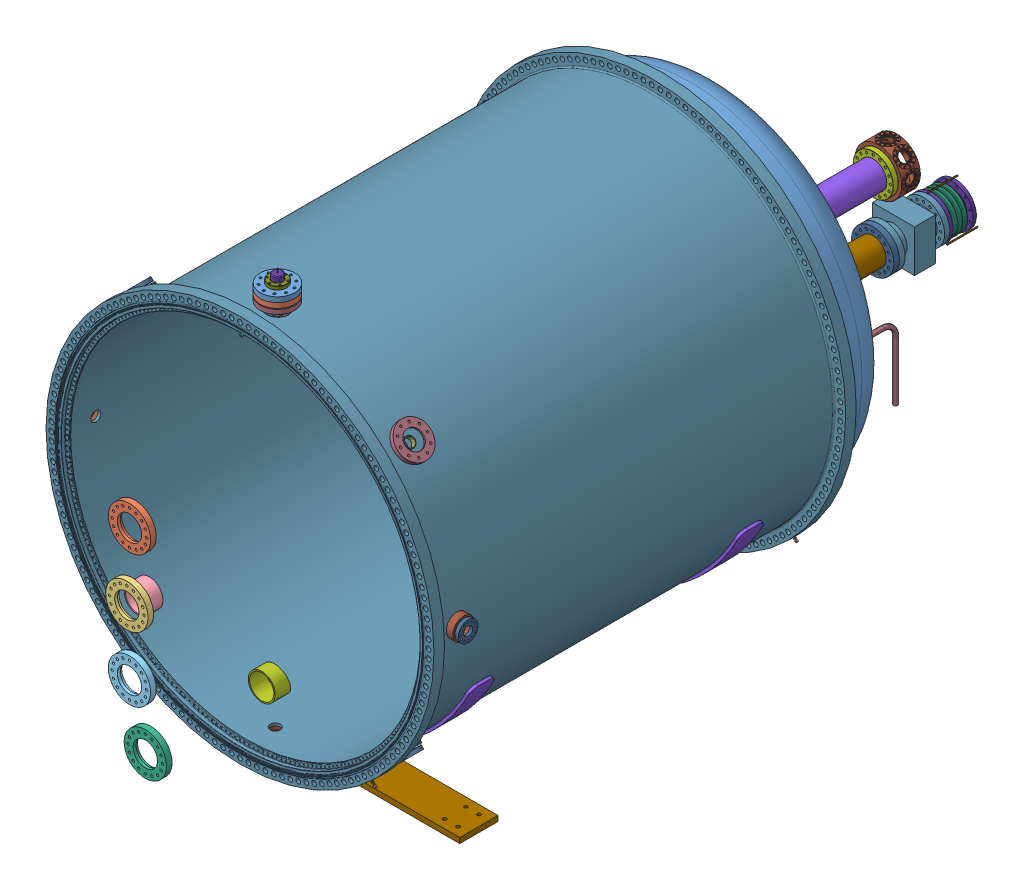
SolidWorks assembly 0201-ASSEMBLAGE, configuration Predeterminado. Lengths in mm.
Overall size (1480 1658.11 3261.35).
238 component instances, 64 part files, 0 mates.
Components (placement in the parent):
- pressure_vessel1_jordi-1: pressure_vessel1_jordi [Predeterminado] at (41.4592 923 146.4) x (-1 0 0) z (0 0 1) size (1480 1658.11 3261.35)
  - mount_hardware-1: mount_hardware [Predeterminado] at (0 -3 0) size (1220 87.2 1155)
    - corner-free-1: corner-free [Predeterminado] at (-0.75 0 12.9) size (150 87 135)
      - key_free.1-1: key_free.1 [Predeterminado] at (0 0 -80) size (20 23.2 20)
      - key_free.1-2: key_free.1 [Predeterminado] at origin size (20 23.2 20)
      - fastener_set.1.1-1: fastener_set.1.1 [Predeterminado] at (0 0 -1040.4) size (50 87 50)
        - washer-1: washer [Predeterminado] at origin size (50 5 50)
        - m16-2_hhexnut-1: m16-2_hhexnut [Predeterminado] at (543.2477 766.8 336.1) size (24 16 27.71)
        - m16-stud-1: m16-stud [Predeterminado] at origin size (16 87 16)
      - fastener_set.1.1-2: fastener_set.1.1 [Predeterminado] at (0 0 -960.4) size (50 87 50)
        - washer-1: washer [Predeterminado] at origin size (50 5 50)
        - m16-2_hhexnut-1: m16-2_hhexnut [Predeterminado] at (543.2477 766.8 336.1) size (24 16 27.71)
        - m16-stud-1: m16-stud [Predeterminado] at origin size (16 87 16)
      - pad-free-1: pad-free [Predeterminado] at (1.4954 0 -288.2) x (-1 0 0) z (0 0 -1) size (150 6 135)
    - corner_hardware_long_slide-1: corner_hardware_long_slide [Predeterminado] at (0.7454 0 -275.3) x (-1 0 0) z (0 0 -1) size (150 87 135)
      - fastener_set.1.1-1: fastener_set.1.1 [Predeterminado] at (1086.4954 0 752.2) x (-1 0 0) z (0 0 -1) size (50 87 50)
        - washer-1: washer [Predeterminado] at origin size (50 5 50)
        - m16-2_hhexnut-1: m16-2_hhexnut [Predeterminado] at (543.2477 766.8 336.1) size (24 16 27.71)
        - m16-stud-1: m16-stud [Predeterminado] at origin size (16 87 16)
      - fastener_set.1.1-2: fastener_set.1.1 [Predeterminado] at (1086.4954 0 672.2) x (-1 0 0) z (0 0 -1) size (50 87 50)
        - washer-1: washer [Predeterminado] at origin size (50 5 50)
        - m16-2_hhexnut-1: m16-2_hhexnut [Predeterminado] at (543.2477 766.8 336.1) size (24 16 27.71)
        - m16-stud-1: m16-stud [Predeterminado] at origin size (16 87 16)
      - bearing_pad_1-1: bearing_pad_1 [Predeterminado] at origin size (150 6 135)
      - key.1-1: key.1 [Predeterminado] at origin size (26 23.2 30)
      - key.1-2: key.1 [Predeterminado] at (0 0 -80) size (26 23.2 30)
    - corner_hardware_transverse_slide-1: corner_hardware_transverse_slide [Predeterminado] at (-1 0 -8) size (149.75 87 135)
      - fastener_set.1.1-1: fastener_set.1.1 [Predeterminado] at (0 0 80) size (50 87 50)
        - washer-1: washer [Predeterminado] at origin size (50 5 50)
        - m16-2_hhexnut-1: m16-2_hhexnut [Predeterminado] at (543.2477 766.8 336.1) size (24 16 27.71)
        - m16-stud-1: m16-stud [Predeterminado] at origin size (16 87 16)
      - fastener_set.1.1-2: fastener_set.1.1 [Predeterminado] at origin size (50 87 50)
        - washer-1: washer [Predeterminado] at origin size (50 5 50)
        - m16-2_hhexnut-1: m16-2_hhexnut [Predeterminado] at (543.2477 766.8 336.1) size (24 16 27.71)
        - m16-stud-1: m16-stud [Predeterminado] at origin size (16 87 16)
      - bearing_pad-1: bearing_pad [Predeterminado] at origin size (149.75 6 135)
      - key-1: key [Predeterminado] at (127.1477 0 959.3477) x (0 0 -1) z (1 0 0) size (26 23.2 30)
      - key-2: key [Predeterminado] at (127.1477 0 879.3477) x (0 0 -1) z (1 0 0) size (26 23.2 30)
    - corner_fixed-1: corner_fixed [Predeterminado] at origin size (150 87 135)
      - fastener_set.1.1-1: fastener_set.1.1 [Predeterminado] at (-1085.75 0.2 72.5) size (50 87 50)
        - washer-1: washer [Predeterminado] at origin size (50 5 50)
        - m16-2_hhexnut-1: m16-2_hhexnut [Predeterminado] at (543.2477 766.8 336.1) size (24 16 27.71)
        - m16-stud-1: m16-stud [Predeterminado] at origin size (16 87 16)
      - fastener_set.1.1-2: fastener_set.1.1 [Predeterminado] at (-1085.75 0.2 -7.5) size (50 87 50)
        - washer-1: washer [Predeterminado] at origin size (50 5 50)
        - m16-2_hhexnut-1: m16-2_hhexnut [Predeterminado] at (543.2477 766.8 336.1) size (24 16 27.71)
        - m16-stud-1: m16-stud [Predeterminado] at origin size (16 87 16)
      - pad-fixed-1: pad-fixed [Predeterminado] at (-0.75 0 -7.5) size (150 6 135)
  - tracking_head_assem_jordi-1: tracking_head_assem_jordi [Predeterminado] at (0 0 -17.4) x (-1 0 0) z (0 0 -1) size (1480 1510.05 550.83)
    - Hexagon_Socket_Head_Cap_Screw_5_16-18x1_255_ANSI_B18.3-1: Hexagon_Socket_Head_Cap_Screw_5_16-18x1_255_ANSI_B18.3 [Predeterminado] at (0 -660 -681.9) x (1 0 0) z (0 0 -1) size (11.91 11.91 39.8)
    - Hexagon_Socket_Head_Cap_Screw_5_16-18x1_255_ANSI_B18.3-2: Hexagon_Socket_Head_Cap_Screw_5_16-18x1_255_ANSI_B18.3 [Predeterminado] at (0 660 -681.5) x (-1 0 0) z (0 0 -1) size (11.91 11.91 39.8)
    - O-ring_press.1.1-1: O-ring_press.1.1 [Predeterminado] at (0 0 61.9) x (-1 0 0) z (0 0 -1) size (1377.4 1377.4 3.81)
    - O-ring_H2o-1: O-ring_H2o [Predeterminado] at (0 0 61.5) x (-1 0 0) z (0 0 -1) size (1392 1392 2.61)
    - head_weldment.1-1: head_weldment.1 [Predeterminado] at (0 0 -17.4) x (-1 0 0) z (0 0 -1) size (1480 1510.05 550.83)
      - reinforcement.axial.1.1.1-1: reinforcement.axial.1.1.1 [Predeterminado] at (0 -13.7355 -284.0742) x (1 0 0) z (0 0.183956 -0.982934) size (203.29 202.99 30.7)
      - nozzle_aux_l.2-1: nozzle_aux_l.2 [Predeterminado] at (0 0 -282.8) x (1 0 0) z (0 0 -1) size (165 165 21.44)
        - flange_aux_2-1: flange_aux_2 [Predeterminado] at (0 0 -69.4114) x (-1 0 0) z (0 0 -1) size (165 165 21.44)
      - nozzle_axial-1: nozzle_axial [Predeterminado] at (0 0 -282.8) x (-1 0 0) z (0 0 -1) size (165 165 85.73)
        - flange_1-1: flange_1 [Predeterminado] at (0 250 -79.4114) x (1 0 0) z (0 0 -1) size (165 165 21.44)
        - tube-1: tube [Predeterminado] at (0 0 -242.4894) size (101.6 101.6 74.63)
      - nozzle_aux_l-1: nozzle_aux_l [Predeterminado] at (0 0 -282.8) x (-1 0 0) z (0 0 -1) size (440 939.85 440)
        - nozzle_auxiliary.1-1: nozzle_auxiliary.1 [Predeterminado] at (0 -250 -242.8779) x (-1 0 0) z (0 0 1) size (440 440 440)
        - nozzle_auxiliary.1-2: nozzle_auxiliary.1 [Predeterminado] at (0 250 -242.8779) size (440 440 440)
        - flange_aux_1-1: flange_aux_1 [Predeterminado] at (0 0 -69.4114) x (-1 0 0) z (0 0 -1) size (165 165 21.44)
      - head_O_ring-1: head_O_ring [Predeterminado] at (0 0 -17.4) x (-1 0 0) z (0 0 -1) size (1480 1480 359.44)
      - nozzle_hv-1: nozzle_hv [Predeterminado] at (0 272.0886 -282.8) x (-1 0 0) z (0 0 -1) size (496.82 496.82 496.82)
        - flange_aux-1: flange_aux [Predeterminado] at (0 0 -9.4114) x (-1 0 0) z (0 0 -1) size (165 165 21.44)
        - nozzle_auxiliary-1: nozzle_auxiliary [Predeterminado] at (0 250 217.1221) size (496.82 496.82 496.82)
      - reinforcement.axial-1: reinforcement.axial [Predeterminado] at (0 0 -282.8) x (-1 0 0) z (0 0 -1) size (203.28 203.96 19.57)
      - reinforcement.axial.1.1.1-2: reinforcement.axial.1.1.1 [Predeterminado] at (0 13.7355 -284.0742) x (-1 0 0) z (0 -0.183956 -0.982934) size (203.29 202.99 30.7)
      - reinforcement.axial.1.2-1: reinforcement.axial.1.2 [Predeterminado] at (0 28.6873 -288.5308) x (-1 0 0) z (0 -0.384203 -0.923249) size (193.14 205.75 36.46)
  - main_cyl_vessel-1: main_cyl_vessel [Predeterminado] at origin size (1480 1618.11 1626.05)
    - barrel_weldment.1-1: barrel_weldment.1 [Predeterminado] at origin size (1480 1537 1600)
      - support.1.1-1: support.1.1 [Predeterminado] at (0 0 882.5) size (1271.75 508.59 147.26)
        - pad-1: pad [Predeterminado] at (0 0 47.5) x (0.999999 0.001635 0) z (0 0 1) size (1271.08 410.55 147.26)
        - base_1-1: base_1 [Predeterminado] at (-0.75 27 0) size (1250 20 145)
        - plate.1-1: plate.1 [Predeterminado] at origin size (1230 442.67 145)
      - support.1-1: support.1 [Predeterminado] at (0 0 -137.5) size (1271.75 508.59 147.26)
        - base.1-1: base.1 [Predeterminado] at (0.7454 27 -1027.8) x (-1 0 0) z (0 0 -1) size (1250 20 145)
        - plate.1-1: plate.1 [Predeterminado] at origin size (1230 442.67 145)
        - pad-1: pad [Predeterminado] at (0 0 47.5) x (0.999999 0.001635 0) z (0 0 1) size (1271.08 410.55 147.26)
      - half_nipple_DN40_mdc_401002.3-1: half_nipple_DN40_mdc_401002.3 [Predeterminado] at (-504.8778 504.8778 525) x (-0.105943 -0.105943 -0.988712) z (-0.707107 0.707107 0) size (85.39 85.39 50.95)
        - flange_flat-1: flange_flat [Predeterminado] at (0 0 10.6864) x (0.988712 -0.149826 0) z (0 0 1) size (75 75 15)
        - tube_3-1: tube_3 [Predeterminado] at origin size (36 36 44.64)
      - half_nipple_DN40_mdc_401002.3-2: half_nipple_DN40_mdc_401002.3 [Predeterminado] at (-714.005 0 525) x (0 -0.149826 -0.988712) z (-1 0 0) size (85.39 85.39 50.95)
        - flange_flat-1: flange_flat [Predeterminado] at (0 0 10.6864) x (0.988712 -0.149826 0) z (0 0 1) size (75 75 15)
        - tube_3-1: tube_3 [Predeterminado] at origin size (36 36 44.64)
      - half_nipple_DN40_mdc_401002.3-3: half_nipple_DN40_mdc_401002.3 [Predeterminado] at (504.8778 -504.8778 525) x (0.105943 0.105943 -0.988712) z (0.707107 -0.707107 0) size (85.39 85.39 50.95)
        - flange_flat-1: flange_flat [Predeterminado] at (0 0 10.6864) x (0.988712 -0.149826 0) z (0 0 1) size (75 75 15)
        - tube_3-1: tube_3 [Predeterminado] at origin size (36 36 44.64)
      - half_nipple_DN40_mdc_401002.3-4: half_nipple_DN40_mdc_401002.3 [Predeterminado] at (714.005 0 525) x (0 0.149826 -0.988712) z (1 0 0) size (85.39 85.39 50.95)
        - flange_flat-1: flange_flat [Predeterminado] at (0 0 10.6864) x (0.988712 -0.149826 0) z (0 0 1) size (75 75 15)
        - tube_3-1: tube_3 [Predeterminado] at origin size (36 36 44.64)
      - half_nipple_DN40_mdc_401002.3-5: half_nipple_DN40_mdc_401002.3 [Predeterminado] at (504.8778 504.8778 525) x (-0.105943 0.105943 -0.988712) z (0.707107 0.707107 0) size (85.39 85.39 50.95)
        - flange_flat-1: flange_flat [Predeterminado] at (0 0 10.6864) x (0.988712 -0.149826 0) z (0 0 1) size (75 75 15)
        - tube_3-1: tube_3 [Predeterminado] at origin size (36 36 44.64)
      - half_nipple_DN40_mdc_401002.3-6: half_nipple_DN40_mdc_401002.3 [Predeterminado] at (0 714.005 525) x (-0.149826 0 -0.988712) z (0 1 0) size (85.39 85.39 50.95)
        - flange_flat-1: flange_flat [Predeterminado] at (0 0 10.6864) x (0.988712 -0.149826 0) z (0 0 1) size (75 75 15)
        - tube_3-1: tube_3 [Predeterminado] at origin size (36 36 44.64)
      - nozzle_DN75.1-1: nozzle_DN75.1 [Predeterminado] at (0 0 0.0857) x (0.707107 -0.707107 0) z (0 0 1) size (178.78 51.96 178.78)
        - tube_2-1: tube_2 [Predeterminado] at (0 -709.9952 516.5143) x (0.400618 0 -0.916245) z (0 -1 0) size (72 72 45.64)
        - flange_flat_DN75-1: flange_flat_DN75 [Predeterminado] at (0 -725.6914 516.5143) x (0.522753 0 -0.852484) z (0 -1 0) size (130 130 16.7)
      - nozzle_DN75.1-2: nozzle_DN75.1 [Predeterminado] at (0 0 0.0857) size (178.78 51.96 178.78)
        - tube_2-1: tube_2 [Predeterminado] at (0 -709.9952 516.5143) x (0.400618 0 -0.916245) z (0 -1 0) size (72 72 45.64)
        - flange_flat_DN75-1: flange_flat_DN75 [Predeterminado] at (0 -725.6914 516.5143) x (0.522753 0 -0.852484) z (0 -1 0) size (130 130 16.7)
      - main_vessel_bolt_flange_Oring-1: main_vessel_bolt_flange_Oring [Predeterminado] at (0 0 -140) size (1480 1480 1600)
    - half_nipple_DN40_mdc_401002.top-1: half_nipple_DN40_mdc_401002.top [Predeterminado] at (0 -729.005 516.6) x (0.400618 0 -0.916245) z (0 -1 0) size (261.68 261.68 242.65)
      - ft_CF75-1: ft_CF75 [Predeterminado] at (473.2537 -206.9251 -714.005) x (0.400618 0.916245 0) z (-0.916245 0.400618 0) size (198.72 242.65 198.72)
        - hv_feedthrough_assem-1: hv_feedthrough_assem [Predeterminado] at (45.0172 -129.75 1.9655) x (0.996195 0 0.087156) z (-0.087156 0 0.996195) size (183.43 242.65 183.43)
          - plunger-1: plunger [Predeterminado] at (0 73.6 0) size (7 109 7)
          - FT-vacom_50kV-1: FT-vacom_50kV [Predeterminado] at (-45.0172 110.4 1.9655) x (0.996195 0 -0.087156) z (0.087156 0 0.996195) size (94.08 221.5 94.08)
            - flange.1-1: flange.1 [Predeterminado] at (0 -744.3722 516.5143) x (-0.47895 0 0.877842) z (0 1 0) size (69.34 69.34 12.7)
            - insulator-1: insulator [Predeterminado] at (45.0172 -129.75 1.9655) x (0.996195 0 0.087156) z (-0.087156 0 0.996195) size (38.35 52 38.35)
            - conductor-1: conductor [Predeterminado] at (45.0172 -129.75 1.9655) x (0.996195 0 0.087156) z (-0.087156 0 0.996195) size (2 221.5 2)
          - DN75-40reducer3-1: DN75-40reducer3 [Predeterminado] at (0 -609.6136 516.5143) x (-0.222469 0 0.97494) z (0 1 0) size (130 130 19.05)
          - DN75_O-ring_adapter-1: DN75_O-ring_adapter [Predeterminado] at (0 -609.6136 516.5143) x (-0.753266 0 0.657716) z (0 -1 0) size (130 130 19.05)
    - pipe_tube5182K834-1: pipe_tube5182K834 [Predeterminado] at (-120.5041 -650.4585 -921.4) x (0.982918 -0.182173 0.026177) z (-0.182236 -0.983255 0) size (24.52 10 20.4)
      - p2_1-1: p2_1 [Predeterminado] at (-599.5111 15.6988 -1073.7738) x (-0.565333 0.04099 0.823844) z (-0.823844 0.021573 -0.566406) size (8.63 9.17 19.4)
      - p1_1-1: p1_1 [Predeterminado] at (-599.5111 15.6988 -1073.7738) x (-0.565333 0.04099 0.823844) z (-0.823844 0.021573 -0.566406) size (7.94 9.17 7.95)
    - pipe_tube5182K834-2: pipe_tube5182K834 [Predeterminado] at (-125.0832 -646.8042 679.3369) x (0.982918 -0.182173 0.026177) z (-0.182236 -0.983255 0) size (24.52 10 20.4)
      - p2_1-1: p2_1 [Predeterminado] at (-599.5111 15.6988 -1073.7738) x (-0.565333 0.04099 0.823844) z (-0.823844 0.021573 -0.566406) size (8.63 9.17 19.4)
      - p1_1-1: p1_1 [Predeterminado] at (-599.5111 15.6988 -1073.7738) x (-0.565333 0.04099 0.823844) z (-0.823844 0.021573 -0.566406) size (7.94 9.17 7.95)
    - SHOULDERBOLT_8XM6X10LG-1: SHOULDERBOLT_8XM6X10LG [Predeterminado] at (0 -670 649.6) x (0.949444 -0.313936 0) z (-0.313936 -0.949444 0) size (10 21.5 10)
  - flange_bolts_16mm-1: flange_bolts_16mm [Predeterminado] at origin size (71.93 1467.41 1731.8)
    - fastener_set_16mm.2-1: fastener_set_16mm.2 [Predeterminado] at (-6.2049 -94.8144 -477.8) x (-0.998993 0.044865 0) z (0 0 -1) size (37.08 37.41 131)
      - washer_17id_28od_4t.1-1: washer_17id_28od_4t.1 [Predeterminado] at (0 -620 422.1) size (28 28 3)
      - washer_17id_28od_4t.1-2: washer_17id_28od_4t.1 [Predeterminado] at (0 -620 505.1) x (-1 0 0) z (0 0 -1) size (28 28 3)
      - stud_M16x1F.1-1: stud_M16x1F.1 [Predeterminado] at (-94.3992 -1323.6965 -306) x (-0.991122 0.132957 0) z (0 0 1) size (16 16 131)
      - nut_M16x1F.1-1: nut_M16x1F.1 [Predeterminado] at (-232.2561 -1194.854 -156.9) x (-0.927184 0.374607 0) z (0 0 1) size (25.63 27.47 13)
      - nut_M16x1F.1-2: nut_M16x1F.1 [Predeterminado] at (-379.8395 -1110.0224 1084.1) x (0.790359 -0.612644 0) z (0 0 -1) size (25.63 27.47 13)
    - fastener_set_16mm.2-2: fastener_set_16mm.2 [Predeterminado] at (0 95 -477.8) x (1 0 0) z (0 0 -1) size (37.08 37.41 131)
      - washer_17id_28od_4t.1-1: washer_17id_28od_4t.1 [Predeterminado] at (0 -620 422.1) size (28 28 3)
      - washer_17id_28od_4t.1-2: washer_17id_28od_4t.1 [Predeterminado] at (0 -620 505.1) x (-1 0 0) z (0 0 -1) size (28 28 3)
      - stud_M16x1F.1-1: stud_M16x1F.1 [Predeterminado] at (-94.3992 -1323.6965 -306) x (-0.991122 0.132957 0) z (0 0 1) size (16 16 131)
      - nut_M16x1F.1-1: nut_M16x1F.1 [Predeterminado] at (-232.2561 -1194.854 -156.9) x (-0.927184 0.374607 0) z (0 0 1) size (25.63 27.47 13)
      - nut_M16x1F.1-2: nut_M16x1F.1 [Predeterminado] at (-379.8395 -1110.0224 1084.1) x (0.790359 -0.612644 0) z (0 0 -1) size (25.63 27.47 13)
    - fastener_set_16mm.2-3: fastener_set_16mm.2 [Predeterminado] at (0 -95 -477.8) x (-1 0 0) z (0 0 -1) size (37.08 37.41 131)
      - washer_17id_28od_4t.1-1: washer_17id_28od_4t.1 [Predeterminado] at (0 -620 422.1) size (28 28 3)
      - washer_17id_28od_4t.1-2: washer_17id_28od_4t.1 [Predeterminado] at (0 -620 505.1) x (-1 0 0) z (0 0 -1) size (28 28 3)
      - stud_M16x1F.1-1: stud_M16x1F.1 [Predeterminado] at (-94.3992 -1323.6965 -306) x (-0.991122 0.132957 0) z (0 0 1) size (16 16 131)
      - nut_M16x1F.1-1: nut_M16x1F.1 [Predeterminado] at (-232.2561 -1194.854 -156.9) x (-0.927184 0.374607 0) z (0 0 1) size (25.63 27.47 13)
      - nut_M16x1F.1-2: nut_M16x1F.1 [Predeterminado] at (-379.8395 -1110.0224 1084.1) x (0.790359 -0.612644 0) z (0 0 -1) size (25.63 27.47 13)
    - fastener_set_16mm.2-4: fastener_set_16mm.2 [Predeterminado] at (0 95 195) x (-1 0 0) z (0 0 1) size (37.08 37.41 131)
      - washer_17id_28od_4t.1-1: washer_17id_28od_4t.1 [Predeterminado] at (0 -620 422.1) size (28 28 3)
      - washer_17id_28od_4t.1-2: washer_17id_28od_4t.1 [Predeterminado] at (0 -620 505.1) x (-1 0 0) z (0 0 -1) size (28 28 3)
      - stud_M16x1F.1-1: stud_M16x1F.1 [Predeterminado] at (-94.3992 -1323.6965 -306) x (-0.991122 0.132957 0) z (0 0 1) size (16 16 131)
      - nut_M16x1F.1-1: nut_M16x1F.1 [Predeterminado] at (-232.2561 -1194.854 -156.9) x (-0.927184 0.374607 0) z (0 0 1) size (25.63 27.47 13)
      - nut_M16x1F.1-2: nut_M16x1F.1 [Predeterminado] at (-379.8395 -1110.0224 1084.1) x (0.790359 -0.612644 0) z (0 0 -1) size (25.63 27.47 13)
    - fastener_set_16mm.2-5: fastener_set_16mm.2 [Predeterminado] at (0 -95 195) size (37.08 37.41 131)
      - washer_17id_28od_4t.1-1: washer_17id_28od_4t.1 [Predeterminado] at (0 -620 422.1) size (28 28 3)
      - washer_17id_28od_4t.1-2: washer_17id_28od_4t.1 [Predeterminado] at (0 -620 505.1) x (-1 0 0) z (0 0 -1) size (28 28 3)
      - stud_M16x1F.1-1: stud_M16x1F.1 [Predeterminado] at (-94.3992 -1323.6965 -306) x (-0.991122 0.132957 0) z (0 0 1) size (16 16 131)
      - nut_M16x1F.1-1: nut_M16x1F.1 [Predeterminado] at (-232.2561 -1194.854 -156.9) x (-0.927184 0.374607 0) z (0 0 1) size (25.63 27.47 13)
      - nut_M16x1F.1-2: nut_M16x1F.1 [Predeterminado] at (-379.8395 -1110.0224 1084.1) x (0.790359 -0.612644 0) z (0 0 -1) size (25.63 27.47 13)
  - energy_head_assem_jordi-1: energy_head_assem_jordi [Predeterminado] at (0 0 -200.4) size (1480 1536.09 1251.86)
    - head_assem-1: head_assem [Predeterminado] at (0 0 200.4) size (1480 1536.09 1251.86)
      - NUT_m8-FT-1: NUT_m8-FT [Predeterminado] at (0 315.1256 -1334.0565) x (1 0 0) z (0 -1 0) size (13 6.97 15.01)
      - pin_retainer-1: pin_retainer [Predeterminado] at (38.5373 38.5373 -1) x (0.707107 -0.707107 0) z (0 0 1) size (1 13 1)
      - pin_retainer-2: pin_retainer [Predeterminado] at (38.5373 -38.5373 -1) x (-0.707107 -0.707107 0) z (0 0 1) size (1 13 1)
      - pin_retainer-3: pin_retainer [Predeterminado] at (-38.5373 -38.5373 -1) x (-0.707107 0.707107 0) z (0 0 1) size (1 13 1)
      - pin_retainer-4: pin_retainer [Predeterminado] at (-38.5373 38.5373 -1) x (0.707107 0.707107 0) z (0 0 1) size (1 13 1)
      - extension_nozzle_axial-1: extension_nozzle_axial [Predeterminado] at (0 0 -30) size (160 160 390)
        - flange_aux.1.1.1-1: flange_aux.1.1.1 [Predeterminado] at (0 250 -70.85) x (1 0 0) z (0 0 -1) size (160 160 21.44)
        - flange_CF_6in-1: flange_CF_6in [Predeterminado] at (0 0 -1730.1451) x (-1 0 0) z (0 0 -1) size (151.64 151.64 19.81)
        - tube_1-1: tube_1 [Predeterminado] at (0 0 -242.4894) size (101.85 101.85 368.46)
      - extension_nozzle_aux_l.1-1: extension_nozzle_aux_l.1 [Predeterminado] at (0 0 -30) size (160 160 400)
        - flange_aux.1.1.1-1: flange_aux.1.1.1 [Predeterminado] at (0 500 -60.85) x (1 0 0) z (0 0 -1) size (160 160 21.44)
        - nozzle_auxiliary_1-1: nozzle_auxiliary_1 [Predeterminado] at (0 250 -242.8779) size (101.85 101.85 378.46)
        - flange_aux_3-1: flange_aux_3 [Predeterminado] at (0 0 -439.4114) x (-1 0 0) z (0 0 -1) size (160 160 21.44)
      - O-ring_H2o-1: O-ring_H2o [Predeterminado] at (0 0 -203.9) x (0.998854 0.047854 0) z (0 0 -1) size (1392 1392 2.61)
      - O-ring_press.1.1-1: O-ring_press.1.1 [Predeterminado] at (0 0 -203.5) x (0.998854 0.047854 0) z (0 0 -1) size (1377.4 1377.4 3.81)
      - KIMBALL_OCTAGON_MCF600-SO200800-C-1: KIMBALL_OCTAGON_MCF600-SO200800-C [Predeterminado] at (0 0 -1795.4511) x (0 0 -1) z (1 0 0) size (190.37 186.76 190.37)
      - hv_feedthrough_assem.aux-1: hv_feedthrough_assem.aux [Predeterminado] at (0 522.0886 -179.1996) size (160 354 1025.39)
        - flange_aux.1-1: flange_aux.1 [Predeterminado] at (0 -250 148.3496) x (-1 0 0) z (0 0 -1) size (160 160 21.44)
        - tefzel-1: tefzel [Predeterminado] at (0 -250 149.1996) size (16.2 282.1 1025.39)
      - head_weldment.1-1: head_weldment.1 [Predeterminado] at (0 0 -282.8) x (-1 0 0) z (0 0 -1) size (1480 1510.05 550.83)
        - reinforcement.axial.1.1.1-1: reinforcement.axial.1.1.1 [Predeterminado] at (0 -13.7355 -284.0742) x (1 0 0) z (0 0.183956 -0.982934) size (203.29 202.99 30.7)
        - nozzle_aux_l.2-1: nozzle_aux_l.2 [Predeterminado] at (0 0 -282.8) x (1 0 0) z (0 0 -1) size (165 165 21.44)
          - flange_aux_2-1: flange_aux_2 [Predeterminado] at (0 0 -69.4114) x (-1 0 0) z (0 0 -1) size (165 165 21.44)
        - nozzle_axial-1: nozzle_axial [Predeterminado] at (0 0 -282.8) x (-1 0 0) z (0 0 -1) size (165 165 85.73)
          - flange_1-1: flange_1 [Predeterminado] at (0 250 -79.4114) x (1 0 0) z (0 0 -1) size (165 165 21.44)
          - tube-1: tube [Predeterminado] at (0 0 -242.4894) size (101.6 101.6 74.63)
        - nozzle_aux_l-1: nozzle_aux_l [Predeterminado] at (0 0 -282.8) x (-1 0 0) z (0 0 -1) size (440 939.85 440)
          - nozzle_auxiliary.1-1: nozzle_auxiliary.1 [Predeterminado] at (0 -250 -242.8779) x (-1 0 0) z (0 0 1) size (440 440 440)
          - nozzle_auxiliary.1-2: nozzle_auxiliary.1 [Predeterminado] at (0 250 -242.8779) size (440 440 440)
          - flange_aux_1-1: flange_aux_1 [Predeterminado] at (0 0 -69.4114) x (-1 0 0) z (0 0 -1) size (165 165 21.44)
        - head_O_ring-1: head_O_ring [Predeterminado] at (0 0 -17.4) x (-1 0 0) z (0 0 -1) size (1480 1480 359.44)
        - nozzle_hv-1: nozzle_hv [Predeterminado] at (0 272.0886 -282.8) x (-1 0 0) z (0 0 -1) size (496.82 496.82 496.82)
          - flange_aux-1: flange_aux [Predeterminado] at (0 0 -9.4114) x (-1 0 0) z (0 0 -1) size (165 165 21.44)
          - nozzle_auxiliary-1: nozzle_auxiliary [Predeterminado] at (0 250 217.1221) size (496.82 496.82 496.82)
        - reinforcement.axial-1: reinforcement.axial [Predeterminado] at (0 0 -282.8) x (-1 0 0) z (0 0 -1) size (203.28 203.96 19.57)
        - reinforcement.axial.1.1.1-2: reinforcement.axial.1.1.1 [Predeterminado] at (0 13.7355 -284.0742) x (-1 0 0) z (0 -0.183956 -0.982934) size (203.29 202.99 30.7)
        - reinforcement.axial.1.2-1: reinforcement.axial.1.2 [Predeterminado] at (0 28.6873 -288.5308) x (-1 0 0) z (0 -0.384203 -0.923249) size (193.14 205.75 36.46)
      - pr_valve-1: pr_valve [Predeterminado] at (0 500 -3050.8787) x (-1 0 0) z (0 0 1) size (160 160 191)
      - Expansion_joint_DN_300-24-1: Expansion_joint_DN_300-24 [Predeterminado] at (0 409.091 -2872.1834) x (0 0 -1) z (1 0 0) size (116.37 226.64 225.59)
        - Bellows_x_3-1: Bellows_x_3 [Predeterminado] at (-867.7643 -159.091 0) x (0 0 1) z (-1 0 0) size (152 152 98.91)
        - Skirt-1: Skirt [Predeterminado] at (-843.2202 -159.091 0) x (0 0 -1) z (-1 0 0) size (150.73 123.2 81.91)
        - Flange_with_bracket-1: Flange_with_bracket [Predeterminado] at origin size (12.82 174.55 171.94)
          - Flange-1: Flange [Predeterminado] at (-921.0383 -159.091 0) size (12.82 160 160)
          - Bracket.2-1: Bracket.2 [Predeterminado] at (-916.6747 -239.0909 0) x (0 0 -1) z (0 -1 0) size (16.36 1.45 14.55)
          - Bracket.2-2: Bracket.2 [Predeterminado] at (-915.2201 -119.091 -69.282) x (0 -0.866025 -0.5) z (0 0.5 -0.866025) size (16.36 1.45 14.55)
          - Bracket.2-3: Bracket.2 [Predeterminado] at (-915.2201 -119.091 69.282) x (0 0.866025 -0.5) z (0 0.5 0.866025) size (16.36 1.45 14.55)
        - Flange_with_bracket-2: Flange_with_bracket [Predeterminado] at (-1741.7131 -238.6365 -137.7768) x (-1 0 0) z (0 -0.866025 0.5) size (12.82 174.55 171.94)
          - Flange-1: Flange [Predeterminado] at (-921.0383 -159.091 0) size (12.82 160 160)
          - Bracket.2-1: Bracket.2 [Predeterminado] at (-916.6747 -239.0909 0) x (0 0 -1) z (0 -1 0) size (16.36 1.45 14.55)
          - Bracket.2-2: Bracket.2 [Predeterminado] at (-915.2201 -119.091 -69.282) x (0 -0.866025 -0.5) z (0 0.5 -0.866025) size (16.36 1.45 14.55)
          - Bracket.2-3: Bracket.2 [Predeterminado] at (-915.2201 -119.091 69.282) x (0 0.866025 -0.5) z (0 0.5 0.866025) size (16.36 1.45 14.55)
        - Fixation_bolt.2-1: Fixation_bolt.2 [Predeterminado] at (300 -240 0) x (0 0 -1) z (0 1 0) size (8.73 116.37 8.73)
          - Pin_bolt-1: Pin_bolt [Predeterminado] at (0 1111.9475 -6.3636) size (4.37 116.37 4.37)
          - Flat_washer_12_mm.3-1: Flat_washer_12_mm.3 [Predeterminado] at (0 1125.0384 -6.3636) x (0 0 -1) z (0 1 0) size (8.73 8.73 0.91)
          - Flat_washer_12_mm.3-2: Flat_washer_12_mm.3 [Predeterminado] at (0 1122.6748 -6.3636) x (0 0 1) z (0 1 0) size (8.73 8.73 0.91)
          - Flat_washer_12_mm.3-3: Flat_washer_12_mm.3 [Predeterminado] at (0 1215.2201 -6.3636) x (0 0 -1) z (0 -1 0) size (8.73 8.73 0.91)
          - Flat_washer_12_mm.3-4: Flat_washer_12_mm.3 [Predeterminado] at (0 1217.5838 -6.3636) x (0 0 -1) z (0 -1 0) size (8.73 8.73 0.91)
          - Flat_nut_M12.2-1: Flat_nut_M12.2 [Predeterminado] at (0 1125.9475 -6.3636) x (0 -1 0) z (0 0 1) size (2.64 6.55 8.08)
          - Flat_nut_M12.2-2: Flat_nut_M12.2 [Predeterminado] at (0 1122.6748 -6.3636) x (0 1 0) z (0 0 1) size (2.64 6.55 8.08)
          - Flat_nut_M12.2-3: Flat_nut_M12.2 [Predeterminado] at (0 1214.311 -6.3636) x (0 1 0) z (0 0 1) size (2.64 6.55 8.08)
          - Flat_nut_M12.2-4: Flat_nut_M12.2 [Predeterminado] at (0 1217.5838 -6.3636) x (0 -1 0) z (0 0 1) size (2.64 6.55 8.08)
        - Fixation_bolt.2-2: Fixation_bolt.2 [Predeterminado] at (300 -118.6365 -70.0692) x (0 0.866025 0.5) z (0 -0.5 0.866025) size (8.73 116.37 8.73)
          - Pin_bolt-1: Pin_bolt [Predeterminado] at (0 1111.9475 -6.3636) size (4.37 116.37 4.37)
          - Flat_washer_12_mm.3-1: Flat_washer_12_mm.3 [Predeterminado] at (0 1125.0384 -6.3636) x (0 0 -1) z (0 1 0) size (8.73 8.73 0.91)
          - Flat_washer_12_mm.3-2: Flat_washer_12_mm.3 [Predeterminado] at (0 1122.6748 -6.3636) x (0 0 1) z (0 1 0) size (8.73 8.73 0.91)
          - Flat_washer_12_mm.3-3: Flat_washer_12_mm.3 [Predeterminado] at (0 1215.2201 -6.3636) x (0 0 -1) z (0 -1 0) size (8.73 8.73 0.91)
          - Flat_washer_12_mm.3-4: Flat_washer_12_mm.3 [Predeterminado] at (0 1217.5838 -6.3636) x (0 0 -1) z (0 -1 0) size (8.73 8.73 0.91)
          - Flat_nut_M12.2-1: Flat_nut_M12.2 [Predeterminado] at (0 1125.9475 -6.3636) x (0 -1 0) z (0 0 1) size (2.64 6.55 8.08)
          - Flat_nut_M12.2-2: Flat_nut_M12.2 [Predeterminado] at (0 1122.6748 -6.3636) x (0 1 0) z (0 0 1) size (2.64 6.55 8.08)
          - Flat_nut_M12.2-3: Flat_nut_M12.2 [Predeterminado] at (0 1214.311 -6.3636) x (0 1 0) z (0 0 1) size (2.64 6.55 8.08)
          - Flat_nut_M12.2-4: Flat_nut_M12.2 [Predeterminado] at (0 1217.5838 -6.3636) x (0 -1 0) z (0 0 1) size (2.64 6.55 8.08)
        - Fixation_bolt.2-3: Fixation_bolt.2 [Predeterminado] at (300 -110.4258 79.4798) x (0 0.612776 -0.790257) z (0 0.790257 0.612776) size (8.73 116.37 8.73)
          - Pin_bolt-1: Pin_bolt [Predeterminado] at (0 1111.9475 -6.3636) size (4.37 116.37 4.37)
          - Flat_washer_12_mm.3-1: Flat_washer_12_mm.3 [Predeterminado] at (0 1125.0384 -6.3636) x (0 0 -1) z (0 1 0) size (8.73 8.73 0.91)
          - Flat_washer_12_mm.3-2: Flat_washer_12_mm.3 [Predeterminado] at (0 1122.6748 -6.3636) x (0 0 1) z (0 1 0) size (8.73 8.73 0.91)
          - Flat_washer_12_mm.3-3: Flat_washer_12_mm.3 [Predeterminado] at (0 1215.2201 -6.3636) x (0 0 -1) z (0 -1 0) size (8.73 8.73 0.91)
          - Flat_washer_12_mm.3-4: Flat_washer_12_mm.3 [Predeterminado] at (0 1217.5838 -6.3636) x (0 0 -1) z (0 -1 0) size (8.73 8.73 0.91)
          - Flat_nut_M12.2-1: Flat_nut_M12.2 [Predeterminado] at (0 1125.9475 -6.3636) x (0 -1 0) z (0 0 1) size (2.64 6.55 8.08)
          - Flat_nut_M12.2-2: Flat_nut_M12.2 [Predeterminado] at (0 1122.6748 -6.3636) x (0 1 0) z (0 0 1) size (2.64 6.55 8.08)
          - Flat_nut_M12.2-3: Flat_nut_M12.2 [Predeterminado] at (0 1214.311 -6.3636) x (0 1 0) z (0 0 1) size (2.64 6.55 8.08)
          - Flat_nut_M12.2-4: Flat_nut_M12.2 [Predeterminado] at (0 1217.5838 -6.3636) x (0 -1 0) z (0 0 1) size (2.64 6.55 8.08)
      - shield_head-1: shield_head [Predeterminado] at origin size (1342.71 1394.62 471.89)
